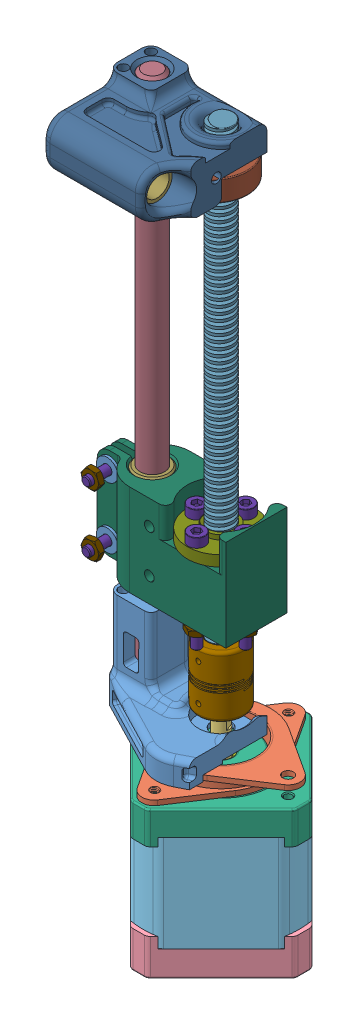
SolidWorks assembly PRUSA 3i horizontal asm, configuration Default. Lengths in mm.
Overall size (67.34 231.9 59.4).
39 component instances, 19 part files, 9 mates.
Components (placement in the parent):
- lead motor assy-1: lead motor assy [Default] at (-0.8403 21.4836 65.5397) size (60.3 83.9 59.73)
  - x motor lead-1: x motor lead [Default] at (1.0016 21.1815 58.4436) size (38.44 32 28.56)
  - Nema 17 Damper v2-1: Nema 17 Damper v2 [Default] at (1.0013 -26.8185 65.4439) x (0.000014 0 -1) z (-1 0 -0.000014) size (52.04 7.74 51.84)
  - 17HM19-2004S-1: 17HM19-2004S [Default] at (-7.0367 -101.7185 75.8822) x (0.703083 0 -0.711108) z (0.711108 0 0.703083) size (42.24 72 42.24)
    - nema17_shaft_17HM19-2004S-1: nema17_shaft_17HM19-2004S [Default] at (13.0746 21 -1.623) x (-0.412738 0 0.91085) z (-0.91085 0 -0.412738) size (5 72 5)
    - nema17_bottom_17HM19-2004S-1: nema17_bottom_17HM19-2004S [Default] at (13.0746 21 -1.623) x (0.999984 0 0.005702) z (-0.005702 0 0.999984) size (42 12 42)
    - nema17_middle_17HM19-2004S-1: nema17_middle_17HM19-2004S [Default] at (13.0746 29.5 -1.623) x (0.999984 0 0.005702) z (-0.005702 0 0.999984) size (42 31.5 42)
    - nema17_top_17HM19-2004S-1: nema17_top_17HM19-2004S [Default] at (13.0746 61 -1.623) x (0.999984 0 0.005702) z (-0.005702 0 0.999984) size (42 12.6 42)
    - radial ball bearing_68_din_DIN 625 - 625 - 8,SI,NC,8_68-1: radial ball bearing_68_din_DIN 625 - 625 - 8,SI,NC,8_68 [Default] at (13.0746 26 -1.623) x (0 -1 0) z (0 0 1) size (5.01 16 16)
    - radial ball bearing_68_din_DIN 625 - 625 - 8,SI,NC,8_68-2: radial ball bearing_68_din_DIN 625 - 625 - 8,SI,NC,8_68 [Default] at (13.0746 67.1 -1.623) x (0 1 0) z (0 0 1) size (5.01 16 16)
    - countersunk flat head cross recess screw_din_ISO 7046-1 - M3 x 30 - Z --- 30N-1: countersunk flat head cross recess screw_din_ISO 7046-1 - M3 x 30 - Z --- 30N [Default] at (28.4859 21.6 13.9651) x (0 1 0) z (0.546944 0 -0.837169) size (30 5.5 5.5)
    - countersunk flat head cross recess screw_din_ISO 7046-1 - M3 x 30 - Z --- 30N-2: countersunk flat head cross recess screw_din_ISO 7046-1 - M3 x 30 - Z --- 30N [Default] at (28.6627 21.6 -17.0344) x (0 1 0) z (0.546944 0 -0.837169) size (30 5.5 5.5)
    - countersunk flat head cross recess screw_din_ISO 7046-1 - M3 x 30 - Z --- 30N-3: countersunk flat head cross recess screw_din_ISO 7046-1 - M3 x 30 - Z --- 30N [Default] at (-2.5136 21.6 13.7883) x (0 1 0) z (0.546944 0 -0.837169) size (30 5.5 5.5)
    - countersunk flat head cross recess screw_din_ISO 7046-1 - M3 x 30 - Z --- 30N-4: countersunk flat head cross recess screw_din_ISO 7046-1 - M3 x 30 - Z --- 30N [Default] at (-2.3368 21.6 -17.2112) x (0 1 0) z (0.546944 0 -0.837169) size (30 5.5 5.5)
  - 5-8 small-1: 5-8 small [Default] at (1.0016 -17.8185 65.4436) x (1 0 0) z (0 1 0) size (15.39 15.39 20)
- x lead idler block-1: x lead idler block [Default] at (-3.2253 161.842 204.8708) x (1 0 0) z (0 0 -1) size (40.45 19.18 38.53)
  - x idler lead mirror-1: x idler lead mirror [Default] at (3.3867 7.1769 80.8876) size (39.97 19.18 36.13)
  - instrument ball bearing_68_iso-1: instrument ball bearing_68_iso [ISO 1224 - 100822 - R,8,SI,NC,8_68] at (2.4627 4.6769 72.4222) x (0 -1 0) z (0 0 1) size (7 22 22)
  - brass sleeve 30mm-1: brass sleeve 30mm [Default] at (3.3867 0.1769 52.8876) x (0 0 1) z (-1 0 0) size (11 11 30)
- liscia da 8 400-1: liscia da 8 400 [Default] at (-22.3386 271.6651 130.9833) x (-0.791136 0 0.611641) z (0 -1 0) size (8 8 167)
- LeadScrew 8mm x 2mmPitch 500-1: LeadScrew 8mm x 2mmPitch 500 [Default] at (0.1614 12.7651 130.9833) x (-0.096506 0 -0.995332) z (0 -1 0) size (9.24 8.22 159.1)
- X CHARIOT ASSY-1: X CHARIOT ASSY [Default] at (-13.6593 122.8824 131.0316) x (1 0 0) z (0 -1 0) size (49.4 23.51 36.69)
  - lead x chariot-1: lead x chariot [Default] at (13.8207 -0.0483 62.5173) size (49.08 20 30.38)
  - brass sleeve 30mm-2: brass sleeve 30mm [Default] at (-8.6793 -0.0483 62.5173) x (0.987351 0.158553 0) z (0 0 1) size (11 11 30)
  - LeadScrew Nut 8mm x 2mmPitch (1)-1: LeadScrew Nut 8mm x 2mmPitch (1) [Default] at (13.8207 -0.0483 69.0173) x (-1 0 0) z (0 0 -1) size (22 22 16.05)
  - socket head cap screw_iso-2: socket head cap screw_iso [ISO 4762 M3 x 30 - 18N] at (5.8207 -0.0483 66.0173) x (0 0 1) z (0.923728 0.383049 0) size (33 5.5 5.5)
  - socket head cap screw_iso-3: socket head cap screw_iso [ISO 4762 M3 x 30 - 18N] at (13.8207 7.9517 66.0173) x (0 0 1) z (0.383049 -0.923728 0) size (33 5.5 5.5)
  - socket head cap screw_iso-4: socket head cap screw_iso [ISO 4762 M3 x 30 - 18N] at (21.8207 -0.0483 66.0173) x (0 0 1) z (-0.923728 -0.383049 0) size (33 5.5 5.5)
  - socket head cap screw_iso-5: socket head cap screw_iso [ISO 4762 M3 x 30 - 18N] at (13.8207 -8.0483 66.0173) x (0 0 1) z (-0.383049 0.923728 0) size (33 5.5 5.5)
  - hex thin nut chamfered gradeab_iso-1: hex thin nut chamfered gradeab_iso [ISO - 4035 - M3 - N] at (21.8207 -0.0483 92.5173) x (-0.923728 -0.383049 0) z (0 0 -1) size (5.5 6.35 1.8)
  - hex thin nut chamfered gradeab_iso-2: hex thin nut chamfered gradeab_iso [ISO - 4035 - M3 - N] at (13.8207 -8.0483 92.5173) x (-0.383049 0.923728 0) z (0 0 -1) size (5.5 6.35 1.8)
  - hex thin nut chamfered gradeab_iso-3: hex thin nut chamfered gradeab_iso [ISO - 4035 - M3 - N] at (5.8207 -0.0483 92.5173) x (0.923728 0.383049 0) z (0 0 -1) size (5.5 6.35 1.8)
  - hex thin nut chamfered gradeab_iso-4: hex thin nut chamfered gradeab_iso [ISO - 4035 - M3 - N] at (13.8207 7.9517 92.5173) x (0.383049 -0.923728 0) z (0 0 -1) size (5.5 6.35 1.8)
  - socket head cap screw_iso-8: socket head cap screw_iso [ISO 4762 M3 x 10 - 10N] at (-19.7187 -2.2811 67.5173) x (0 1 0) z (0.395734 0 0.918365) size (13 5.5 5.5)
  - socket head cap screw_iso-9: socket head cap screw_iso [ISO 4762 M3 x 10 - 10N] at (-19.7187 -2.2811 87.5173) x (0 1 0) z (0.6 0 0.8) size (13 5.5 5.5)
  - plain washer 10673 type snl_iso-3: plain washer 10673 type snl_iso [ISO 10673-3.2-S] at (-19.7187 2.9517 67.5173) x (0 1 0) z (0 0 1) size (0.8 7 7)
  - plain washer 10673 type snl_iso-4: plain washer 10673 type snl_iso [ISO 10673-3.2-S] at (-19.7187 2.9517 87.5173) x (0 1 0) z (0 0 1) size (0.8 7 7)
  - hex thin nut chamfered gradeab_iso-8: hex thin nut chamfered gradeab_iso [ISO - 4035 - M3 - N] at (-19.7187 7.5189 67.5173) x (0.918365 0 -0.395734) z (0 -1 0) size (5.5 6.35 1.8)
  - hex thin nut chamfered gradeab_iso-9: hex thin nut chamfered gradeab_iso [ISO - 4035 - M3 - N] at (-19.7187 7.5189 87.5173) x (0.8 0 -0.6) z (0 -1 0) size (5.5 6.35 1.8)
Mates (geometry in assembly coordinates):
- Coincidente1: coincident aligned: plane of lead motor assy-1/x motor lead-1 through (0.1614 42.6651 123.9833) normal (0 0 -1); plane of x lead idler block-1/x idler lead mirror-1 through (0.1614 154.6651 123.9833) normal (0 0 -1)
- Coincidente2: coincident aligned: plane of lead motor assy-1/x motor lead-1 through (-29.8386 82.6651 137.9833) normal (-1 0 0); plane of x lead idler block-1/x idler lead mirror-1 through (-29.8386 104.6651 137.9833) normal (-1 0 0)
- Distanza1: distance = 130 mm anti-aligned: plane of lead motor assy-1/5-8 small-1 through (0.1614 23.6651 130.9833) normal (0 1 0); plane of x lead idler block-1/x idler lead mirror-1 through (-15.8386 153.6651 88.2062) normal (0 -1 0)
- Concentrico2: concentric aligned: cylinder of lead motor assy-1/x motor lead-1 through (-22.3386 7.6651 130.9833) axis (0 1 0) radius 4.05; cylinder of liscia da 8 400-1 through (-22.3386 -5.6486 130.9833) axis (0 1 0) radius 4
- Coincidente4: coincident anti-aligned: plane of lead motor assy-1/17HM19-2004S-1/nema17_shaft_17HM19-2004S-1 through (0.1614 12.7651 130.9833) normal (0 1 0); plane of LeadScrew 8mm x 2mmPitch 500-1 through (0.1614 12.7651 130.9833) normal (0 -1 0)
- Concentrico4: concentric aligned: cylinder of x lead idler block-1/instrument ball bearing_68_iso-2 through (0.1614 224.3026 130.9833) axis (0 -1 0) radius 4; cylinder of LeadScrew 8mm x 2mmPitch 500-1 through (0.1614 180.9788 130.9833) axis (0 -1 0) radius 4
- Parallelo1: parallel aligned: plane of lead motor assy-1/x motor lead-1 through (0.1614 42.6651 123.9833) normal (0 0 -1); plane of X CHARIOT ASSY-1/lead x chariot-1 through (-29.8386 30.3651 120.9833) normal (0 0 -1)
- Concentrico24: concentric anti-aligned: cylinder of liscia da 8 400-1 through (-22.3386 -5.6486 130.9833) axis (0 1 0) radius 4; cylinder of X CHARIOT ASSY-1/brass sleeve 30mm-2 through (-22.3386 60.3651 130.9833) axis (0 -1 0) radius 4
- LimitDistance1: limit distance = 93.3 mm anti-aligned: plane of x lead idler block-1/x idler lead mirror-1 through (-15.8386 153.6651 88.2062) normal (0 -1 0); plane of X CHARIOT ASSY-1/lead x chariot-1 through (0.1614 60.3651 130.9833) normal (0 1 0)
